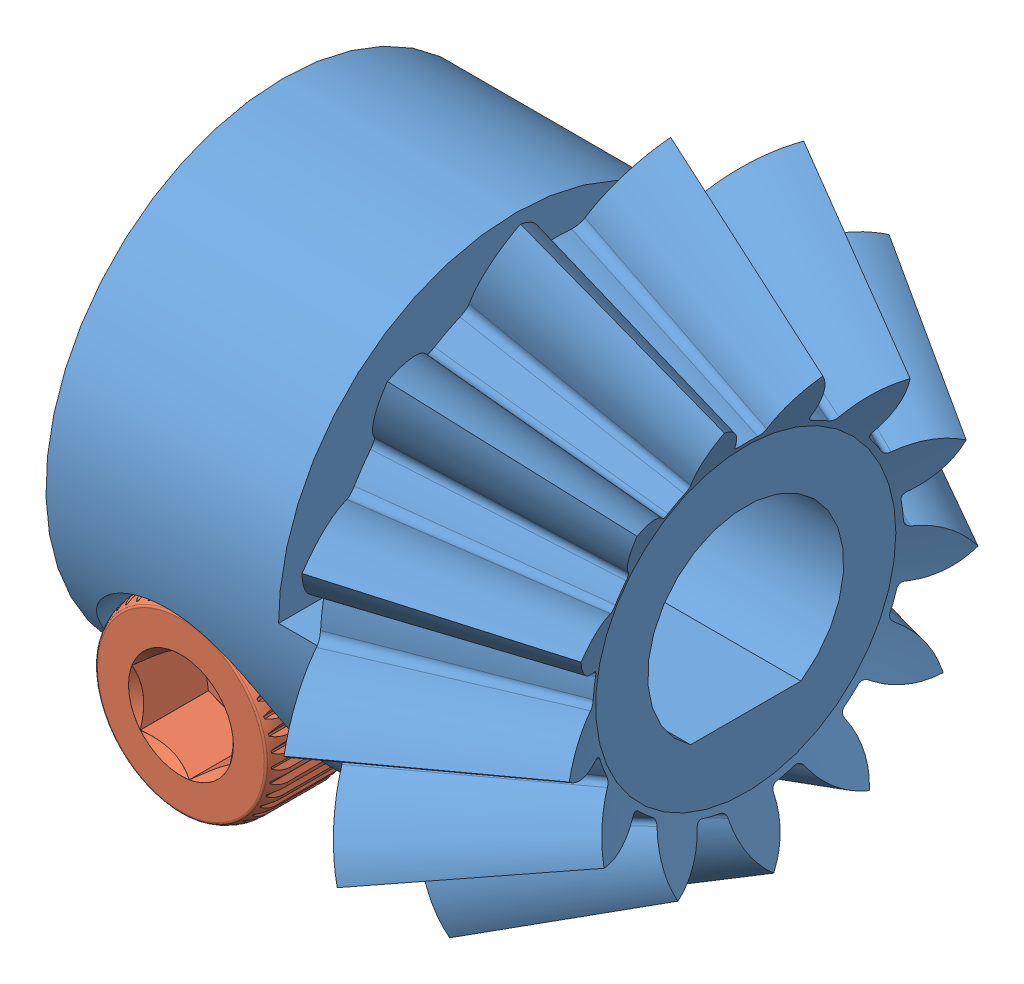
SolidWorks assembly 615458 assembly, configuration Default. Lengths in mm.
Overall size (15.17 19.08 19.22).
2 component instances, 2 part files, 0 mates.
Components (placement in the parent):
- 615458-1: 615458 [Default] at (-61.4441 5.8673 28.8984) size (15.14 19.08 19.22)
- 632110_90128A121-1: 632110_90128A121 [Default] at (-66.148 1.368 -6.0266) x (-0.354662 -0.934995 0) z (0 0 -1) size (5.57 5.57 13.03)
